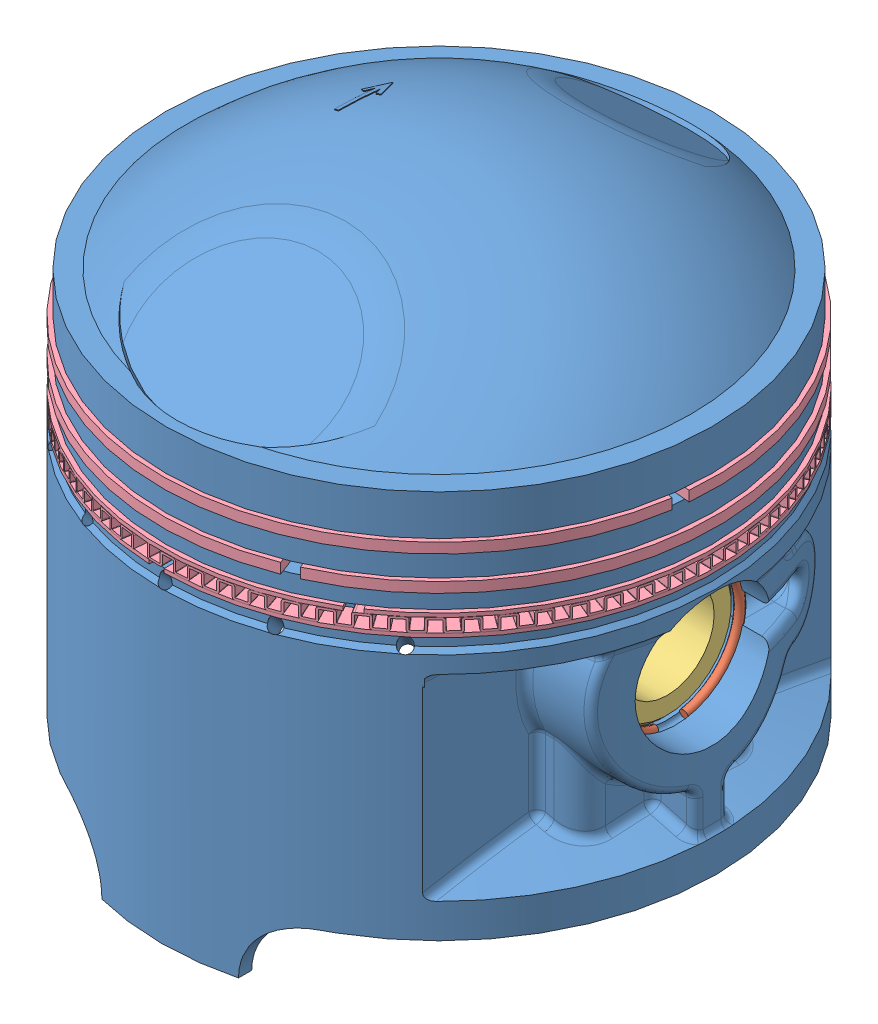
SolidWorks assembly 12111-45002, configuration Default. Lengths in mm.
Overall size (100.8 64.59 100.8).
10 component instances, 4 part files, 13 mates.
Components (placement in the parent):
- 12111-45002-1: 12111-45002 [12111-45002] at origin size (65 64.59 65.08)
- 09381-16002-1: 09381-16002 [CIRCLIP] at (27.25 -36.2 0) x (0 -0.181045 0.983475) z (1 0 0) size (17 17 1)
- 09381-16002-2: 09381-16002 [CIRCLIP] at (-27.25 -36.2 0) x (0 0.992445 -0.122687) z (1 0 0) size (17 17 1)
- 12151-29001-1: 12151-29001 [PIN, piston] at (0 -36.2 0) x (0 0 1) z (-1 0 0) size (16 16 53.5)
- 12140-45013-1: 12140-45013 [PISTON RING SET (STD)] at (0 -23.975 0) x (0.858599 0 -0.512648) z (0.512648 0 0.858599) size (91.48 9.7 91.48) (flexible)
  - 12111-45013-1: 12111-45013 [oliescchraapveer] x (1 0 0) z (0 -1 0) size (65 65 0.45)
  - 12111-45013-2: 12111-45013 [oliescchraapveer] at (0 -2.05 0) x (0.834189 0 0.551479) z (0 -1 0) size (65 65 0.45)
  - 12111-45013-3: 12111-45013 [olieschraapveer veer] at (0 -1.025 0) x (0.798511 0 0.60198) z (0 -1 0) size (65 65 1.63)
  - 12111-45013-4: 12111-45013 [zuigerveer] at (0 6.825 0) x (0.634342 0 -0.773053) z (0 -1 0) size (65 65 1.2)
  - 12111-45013-5: 12111-45013 [zuigerveer] at (0 2.825 0) x (0.985865 0 0.167541) z (0 -1 0) size (65 65 1.2)
Mates (geometry in assembly coordinates):
- Coincident2: coincident aligned: plane of 12111-45002-1 through (0 0 0) normal (0 0 1)
- Coincident3: coincident aligned: plane of 12111-45002-1 through (0 0 0) normal (1 0 0)
- Coincident4: coincident aligned: plane of 12111-45002-1 through (0 0 0) normal (0 1 0)
- Coincident5: coincident: axis of 12111-45002-1 through (32.0411 -36.2 0) axis (-1 0 0); axis of 09381-16002-1 through (22.4375 -36.2 0) axis (1 0 0)
- Tangent3: tangent: torus of 12111-45002-1; circle of 09381-16002-1
- Coincident6: coincident: axis of 12111-45002-1 through (-22.4589 -36.2 0) axis (-1 0 0); axis of 09381-16002-2 through (-32.0625 -36.2 0) axis (1 0 0)
- Tangent5: tangent: torus of 12111-45002-1; circle of 09381-16002-2
- Coincident7: coincident: line of 12111-45002-1 through (-22.4589 -36.2 0) axis (-1 0 0); line of 12151-29001-1 through (-26.25 -36.2 0) axis (1 0 0)
- Coincident8: coincident anti-aligned: plane of 12111-45002-1 through (0 0 0) normal (1 0 0); plane of 12151-29001-1 through (0 -36.2 0) normal (-1 0 0)
- Coincident9: coincident aligned: line of 12111-45002-1 through (44.5573 0 -22.5477) axis (0 0 1); line of 12140-45013-1/12111-45013-3 through (1.6 0 -25.8) axis (0 0 1)
- Width1: width aligned: plane of 12140-45013-1/12111-45013-4 through (29.5692 -16.55 4.4354) normal (0 1 0); plane of 12111-45002-1 through (32.1404 -17.75 4.8211) normal (0 -1 0); plane of 12140-45013-1/12111-45013-4 through (0 -17.75 0) normal (0 1 0); plane of 12111-45002-1 through (0 -16.55 0) normal (0 -1 0)
- Width2: width anti-aligned: plane of 12140-45013-1/12111-45013-5 through (10.8104 -20.55 27.8773) normal (0 1 0); plane of 12111-45002-1 through (11.7504 -21.75 30.3014) normal (0 -1 0); plane of 12140-45013-1/12111-45013-5 through (0 -20.55 0) normal (0 -1 0); plane of 12111-45002-1 through (0 -21.75 0) normal (0 1 0)
- Width3: width aligned: plane of 12140-45013-1/12111-45013-1 through (16.6611 -23.75 27.9045) normal (0 1 0); plane of 12111-45002-1 through (-1.4902 -26.25 32.4658) normal (0 -1 0); plane of 12140-45013-1/12111-45013-2 through (0 -26.25 0) normal (0 1 0); plane of 12111-45002-1 through (0 -23.75 0) normal (0 -1 0)
